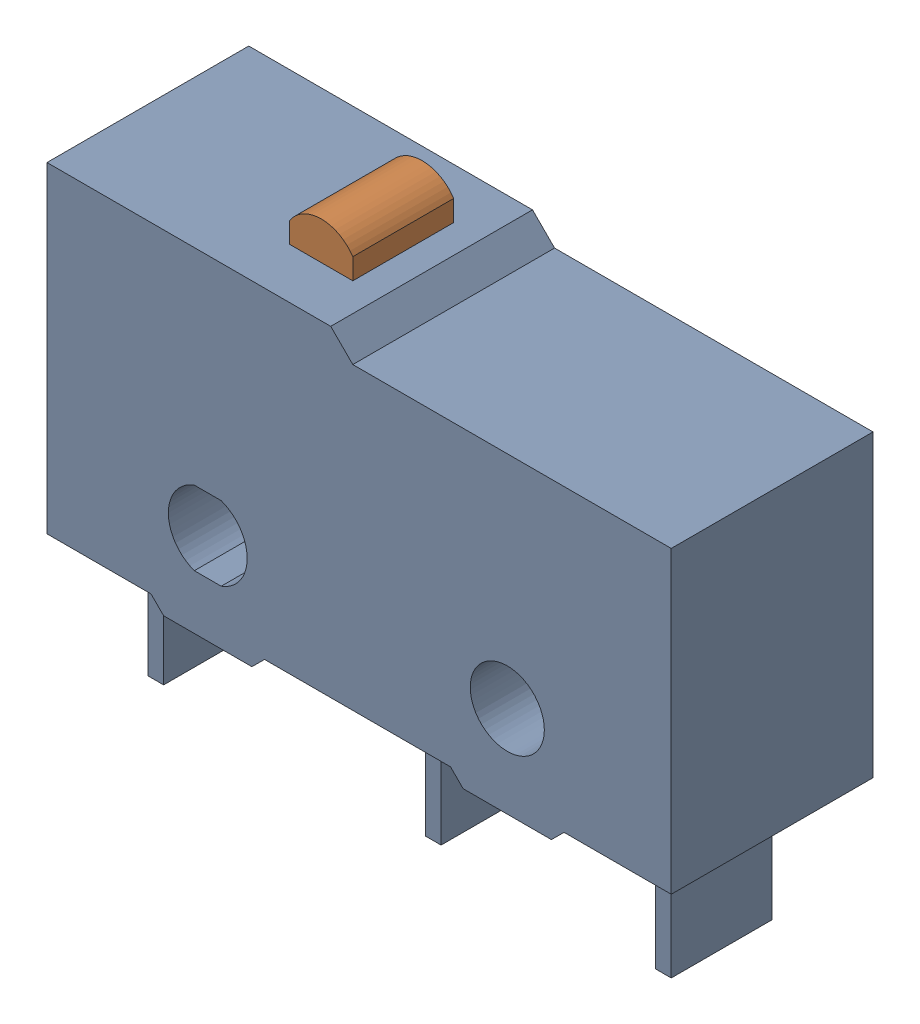
SolidWorks assembly SS_01, configuration Default. Lengths in mm.
Overall size (19.8 15.3 6.4).
2 component instances, 2 part files, 3 mates.
Components (placement in the parent):
- SS_01_BASE-1: SS_01_BASE [Default] at origin size (19.8 14.1 6.4)
- SS_01_ACTUATOR-1: SS_01_ACTUATOR [Default] at (-7.5 8.9 0) size (2 5 3.2)
Mates (geometry in assembly coordinates):
- Coincident1: coincident anti-aligned: plane of SS_01_BASE-1 through (-8.5 2.7 1.6) normal (1 0 0); plane of SS_01_ACTUATOR-1 through (-8.5 8.9 1.6) normal (-1 0 0)
- Coincident2: coincident anti-aligned: plane of SS_01_BASE-1 through (-6.5 2.7 1.6) normal (0 0 -1); plane of SS_01_ACTUATOR-1 through (-8.5 3.9 1.6) normal (0 0 1)
- Distance1: distance = 8.9 mm aligned: plane of SS_01_BASE-1; plane of SS_01_ACTUATOR-1
